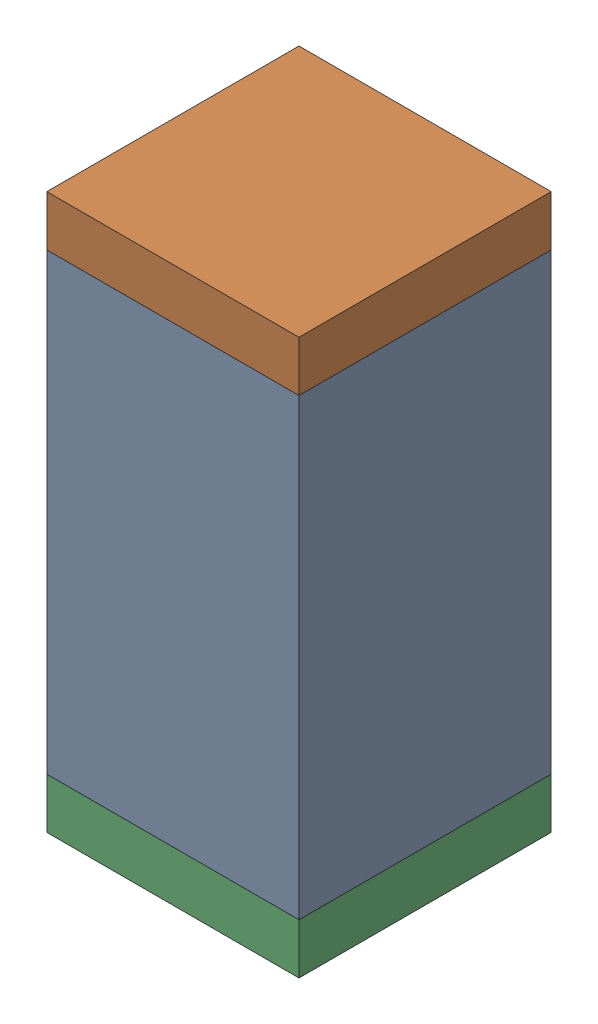
SolidWorks assembly C31, configuration Default. Lengths in mm.
Overall size (0.5 1.1 0.5).
6 component instances, 2 part files, 0 mates.
Components (placement in the parent):
- 791586336-1: 791586336 [Default] at (113.05 27.7 0) size (0.5 0.9 0.5)
  - Extruded_8-1: Extruded_8 [Default] at origin size (0.5 0.9 0.5)
- 810157360-1: 810157360 [Default] at (113.05 28.2 0) size (0.5 0.1 0.5)
  - Extruded_9-1: Extruded_9 [Default] at origin size (0.5 0.1 0.5)
- 810157360-2: 810157360 [Default] at (113.05 27.2 0) size (0.5 0.1 0.5)
  - Extruded_9-1: Extruded_9 [Default] at origin size (0.5 0.1 0.5)
